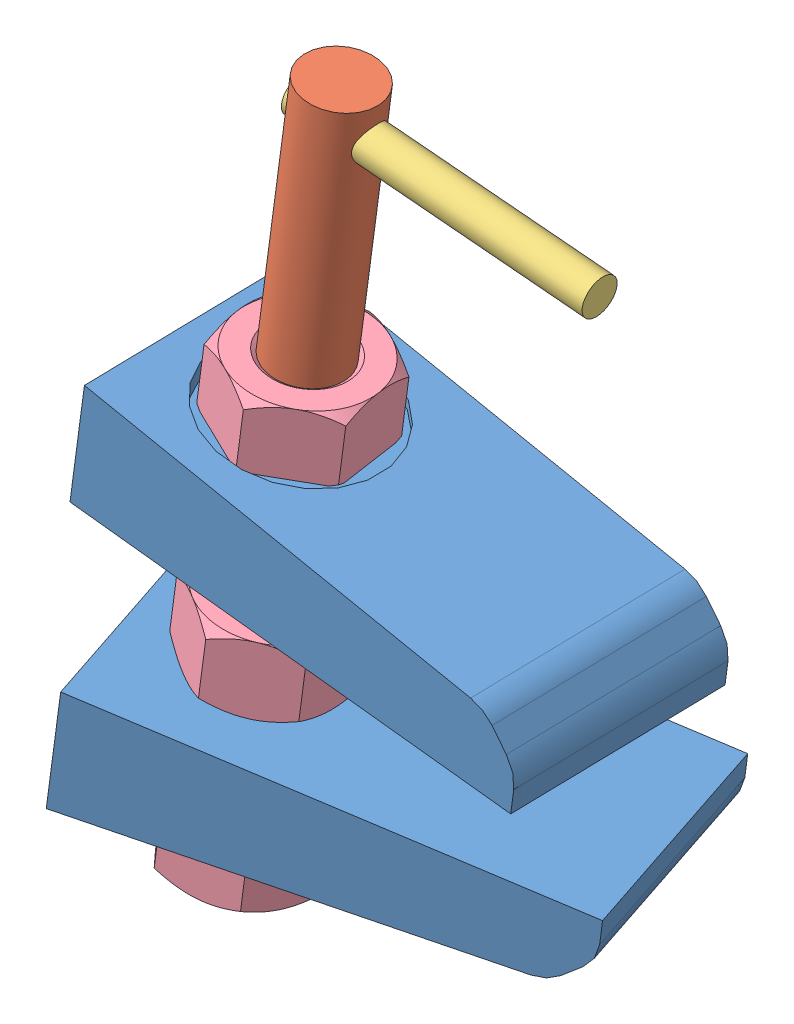
SolidWorks assembly clamps, configuration По умолчанию. Lengths in mm.
Overall size (69.97 100.83 46.29).
7 component instances, 4 part files, 7 mates.
Components (placement in the parent):
- clamps-1: clamps [По умолчанию] at (-33.6098 26.5739 -16.7258) x (0.132342 0.991204 0.000141) z (0.018121 -0.002561 0.999833) size (15 60 30)
- clamps-2: clamps [По умолчанию] at (-30.8793 6.7104 16.7365) x (-0.132342 -0.991204 -0.000141) z (-0.290907 0.038977 -0.955957) size (15 60 30)
- bolt-1: bolt [По умолчанию] at (-24.287 -18.9988 -2.009) x (-0.042521 0.005819 -0.999079) z (0.990292 -0.132214 -0.042917) size (10 100 10)
- pin-1: pin [По умолчанию] at (-16.6659 75.8266 -1.781) x (-0.032539 -0.52065 0.85315) z (0.990292 -0.132214 -0.042917) size (5 5 40)
- hex nut_ai-1: hex nut_ai [HNUT 0.4375-14-D-N] at (-22.9263 -8.8075 -2.0075) x (0.941886 -0.125802 0.311487) z (0.132342 0.991204 0.000141) size (17.48 20.18 9.78)
- hex nut_ai-2: hex nut_ai [HNUT 0.4375-14-D-N] at (-15.6905 45.3866 -1.9998) x (0.982488 -0.13116 -0.132342) z (0.132342 0.991204 0.000141) size (17.48 20.18 9.78)
- hex nut_ai-3: hex nut_ai [HNUT 0.4375-14-D-N] at (-19.6936 15.4041 -2.0041) x (0.990922 -0.132301 -0.023864) z (0.132342 0.991204 0.000141) size (17.48 20.18 9.78)
Mates (geometry in assembly coordinates):
- Концентричный2: concentric anti-aligned: cylinder of clamps-1 through (-15.6932 45.366 -1.9998) axis (-0.132342 -0.991204 -0.000141) radius 5; cylinder of clamps-2 through (-23.8088 -15.4173 -2.0084) axis (0.132342 0.991204 0.000141) radius 5
- Концентричный3: concentric aligned: cylinder of clamps-1 through (-15.6932 45.366 -1.9998) axis (-0.132342 -0.991204 -0.000141) radius 5; cylinder of bolt-1 through (-11.0528 80.1216 -1.9949) axis (-0.132342 -0.991204 -0.000141) radius 5
- Концентричный4: concentric aligned: cylinder of bolt-1 through (-1.8116 73.8434 -2.4248) axis (-0.990292 0.132214 0.042917) radius 2.5; cylinder of pin-1 through (22.9457 70.5381 -3.4977) axis (-0.990292 0.132214 0.042917) radius 2.5
- Касательность1: tangent aligned: cylinder of bolt-1 through (-11.0528 80.1216 -1.9949) axis (-0.132342 -0.991204 -0.000141) radius 5; plane of pin-1 through (-16.6659 75.8266 -1.781) normal (-0.990292 0.132214 0.042917)
- Концентричный5: concentric anti-aligned: cylinder of bolt-1 through (-11.0528 80.1216 -1.9949) axis (-0.132342 -0.991204 -0.000141) radius 5; cylinder of hex nut_ai-1 through (-24.2205 -18.5005 -2.0089) axis (0.132342 0.991204 0.000141) radius 4.6736
- Концентричный6: concentric anti-aligned: cylinder of bolt-1 through (-11.0528 80.1216 -1.9949) axis (-0.132342 -0.991204 -0.000141) radius 5; cylinder of hex nut_ai-2 through (-16.9847 35.6936 -2.0012) axis (0.132342 0.991204 0.000141) radius 4.6736
- Концентричный7: concentric anti-aligned: cylinder of bolt-1 through (-11.0528 80.1216 -1.9949) axis (-0.132342 -0.991204 -0.000141) radius 5; cylinder of hex nut_ai-3 through (-20.9878 5.7111 -2.0054) axis (0.132342 0.991204 0.000141) radius 4.6736
